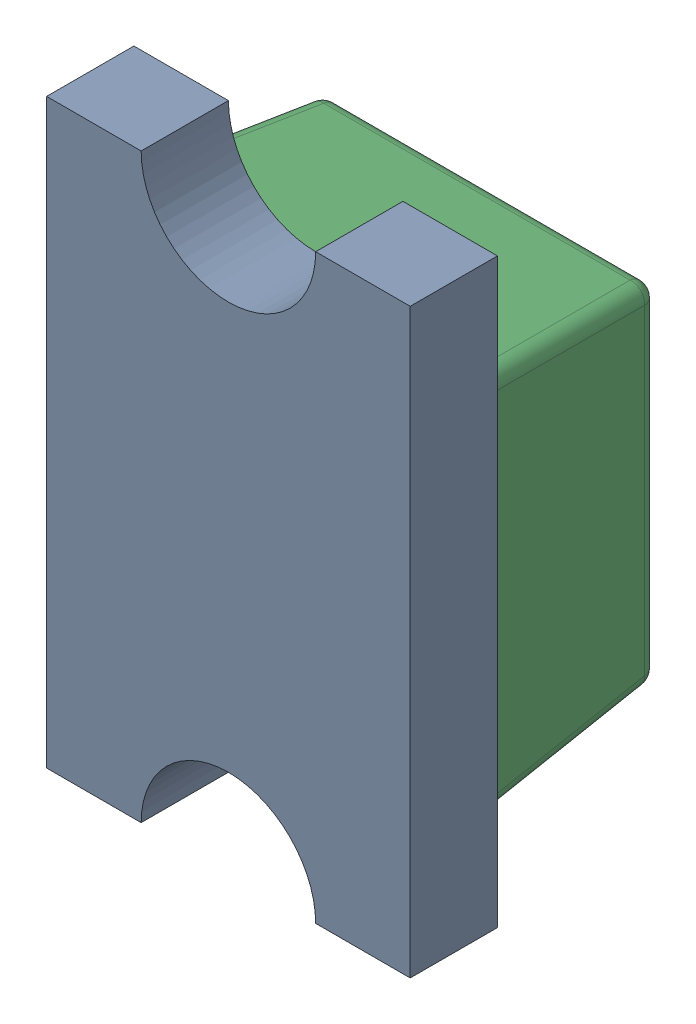
SolidWorks assembly D2_XLR3, configuration Default. Lengths in mm.
Overall size (1.25 2 0.9).
2 component instances, 2 part files, 0 mates.
Components (placement in the parent):
- LED 0805 Base RED-1: LED 0805 Base RED [Default] at (101.043 70.1039 -1.2114) x (0 -1 0) z (1 0 0) size (2 0.4 1.25)
- LED 0805 Lens RED-1: LED 0805 Lens RED [Default] at (101.043 70.1039 -1.2114) x (0 -1 0) z (1 0 0) size (1.3 0.6 1.25)
